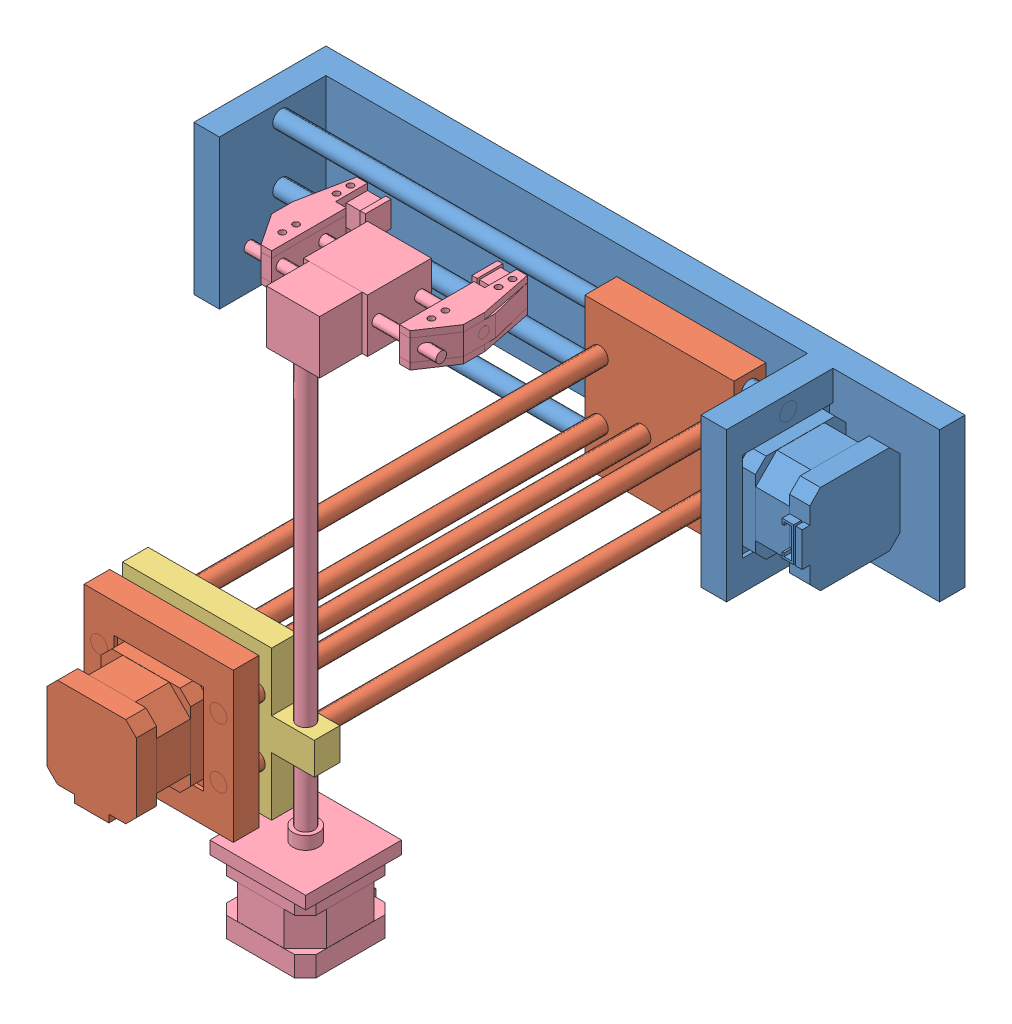
SolidWorks assembly Ensamblaje_Cartesiano, configuration Predeterminado. Lengths in mm.
Overall size (300 259.5 307).
4 component instances, 4 part files, 6 mates.
Components (placement in the parent):
- Pieza_Link1.2-1: Pieza_Link1.2 [Predeterminado] at (-66.2948 -14.0888 269) size (300 70 62)
- Pieza_Link2.2-1: Pieza_Link2.2 [Predeterminado] at (5.7052 -14.0888 294.5) size (70 70 281.5)
- Union-1: Union [Predeterminado] at (5.7052 -14.0888 514.5) x (-1 0 0) z (0 1 0) size (90 12 70)
- Pieza_Link3.2-1: Pieza_Link3.2 [Predeterminado] at (50.7052 -61.0888 520.5) size (90 259.5 87.5)
Mates (geometry in assembly coordinates):
- Concéntrica1: concentric aligned: cylinder of Pieza_Link1-1 through (58.7052 -14.0888 302) axis (-1 0 0) radius 4; cylinder of Pieza_Link2-1 through (52.0189 -14.0888 302) axis (-1 0 0) radius 4
- Concéntrica2: concentric aligned: cylinder of Pieza_Link1-1 through (58.7052 13.9112 302) axis (-1 0 0) radius 4; cylinder of Pieza_Link2-1 through (52.0189 13.9112 302) axis (-1 0 0) radius 4
- Concéntrica3: concentric aligned: cylinder of Pieza_Link2-1 through (5.7052 -14.0888 532.5) axis (0 0 -1) radius 4; cylinder of Union-1 through (5.7052 -14.0888 526.5) axis (0 0 -1) radius 4
- Coincidente4: coincident aligned: plane of Pieza_Link2-1 through (40.7052 20.9112 544.5) normal (0 1 0); plane of Union-1 through (40.7052 20.9112 526.5) normal (0 1 0)
- Concéntrica4: concentric anti-aligned: cylinder of Union-1 through (50.7052 -32.9025 520.5) axis (0 1 0) radius 4; cylinder of Pieza_Link3-1 through (50.7052 159.9112 520.5) axis (0 -1 0) radius 4
- Paralelo1: parallel aligned: plane of Union-1 through (5.7052 -14.0888 526.5) normal (0 0 1); plane of Pieza_Link3.2-1 through (50.7052 154.4112 526.5) normal (0 0 1)
